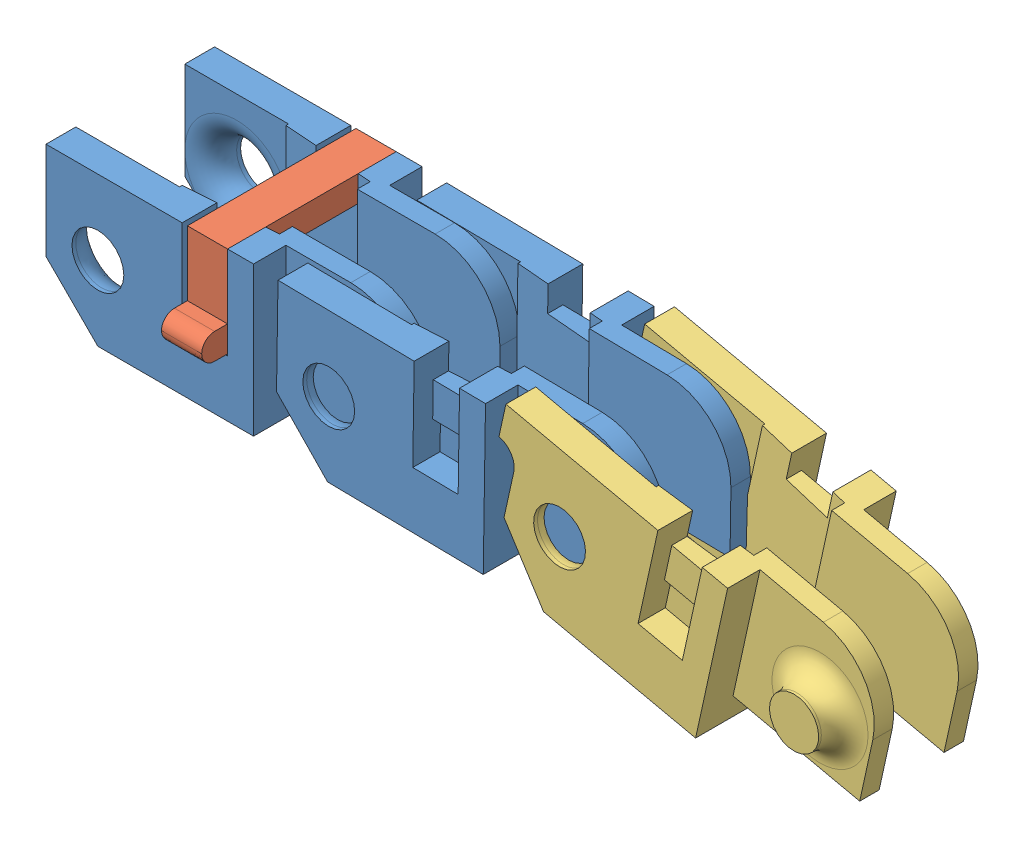
SolidWorks assembly Ensamblaje1, configuration Predeterminado. Lengths in mm.
Overall size (62.72 17.13 15).
4 component instances, 3 part files, 8 mates.
Components (placement in the parent):
- Eslabon 5-1: Eslabon 5 [Predeterminado] at origin size (26 11.5 13)
- Eslabon 5-2: Eslabon 5 [Predeterminado] at (17.913 0.0615 0.2) x (0.999884 -0.015216 0) z (0 0 1) size (26 11.5 13)
- Cierre 5-1: Cierre 5 [Predeterminado] at (14 11.5 -2.5) x (-1 0 0) z (0 0 1) size (3.1 7 15)
- Eslabon 5 Bloqueado-1: Eslabon 5 Bloqueado [Predeterminado] at (34.8577 0.7179 0.4) x (0.976728 -0.214483 0) z (0 0 1) size (27.5 11.5 13)
Mates (geometry in assembly coordinates):
- Concéntrica4: concentric anti-aligned: circle of Eslabon 5-1; cylinder of Eslabon 5-2 through (22 5.75 16.3569) axis (0 0 -1) radius 2
- Coincidente3: coincident anti-aligned: plane of Eslabon 5-1 through (26 1.5 0) normal (0 0 -1); plane of Eslabon 5-2 through (17.7912 -7.94 0) normal (0 0 1)
- Coincidente4: coincident aligned: plane of Eslabon 5-1 through (0 11.5 0) normal (0 1 0); plane of Cierre 5-1 through (14 11.5 -2.5) normal (0 1 0)
- Coincidente5: coincident aligned: plane of Eslabon 5-1 through (16 1.5 -2.5) normal (0 0 -1); plane of Cierre 5-1 through (14 9.5 -2.5) normal (0 0 -1)
- Coincidente6: coincident anti-aligned: plane of Eslabon 5-1 through (14 9.5 -2.5) normal (-1 0 0); plane of Cierre 5-1 through (14 9.5 -2.5) normal (1 0 0)
- Concéntrica5: concentric aligned: circle of Eslabon 5-2; circle of Eslabon 5 Bloqueado-1
- Concéntrica6: concentric aligned: circle of Eslabon 5-2; circle of Eslabon 5 Bloqueado-1
- Coincidente9: coincident anti-aligned: plane of Eslabon 5-2 through (43.9328 1.1657 0.2) normal (0 0 -1); plane of Eslabon 5 Bloqueado-1 through (33.1413 -7.0984 0.2) normal (0 0 1)
